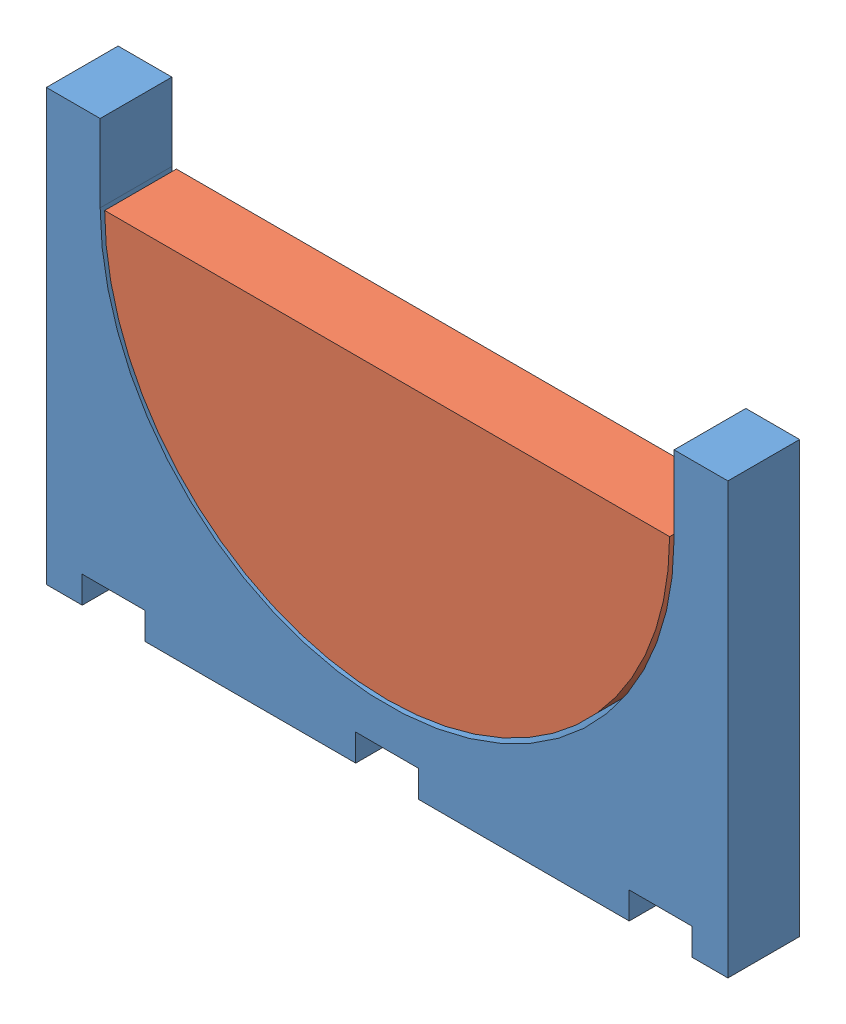
SolidWorks assembly Assem1, configuration Default. Lengths in mm.
Overall size (965.1 609.6 101.6).
2 component instances, 2 part files, 2 mates.
Components (placement in the parent):
- Shroud Foam-1: Shroud Foam [Default] at (-369.884 -112.2562 271.448) size (965.1 609.6 101.6)
- Shroud Foam inner-2: Shroud Foam inner [Default] at (112.666 387.7438 271.448) size (800 400 101.6)
Mates (geometry in assembly coordinates):
- Concentric2: concentric anti-aligned: circle of Shroud Foam-1; circle of Shroud Foam inner-2
- Coincident4: coincident aligned: plane of Shroud Foam-1 through (112.666 387.7438 373.048) normal (0 0 1); plane of Shroud Foam inner-2 through (112.666 387.7438 373.048) normal (0 0 1)
